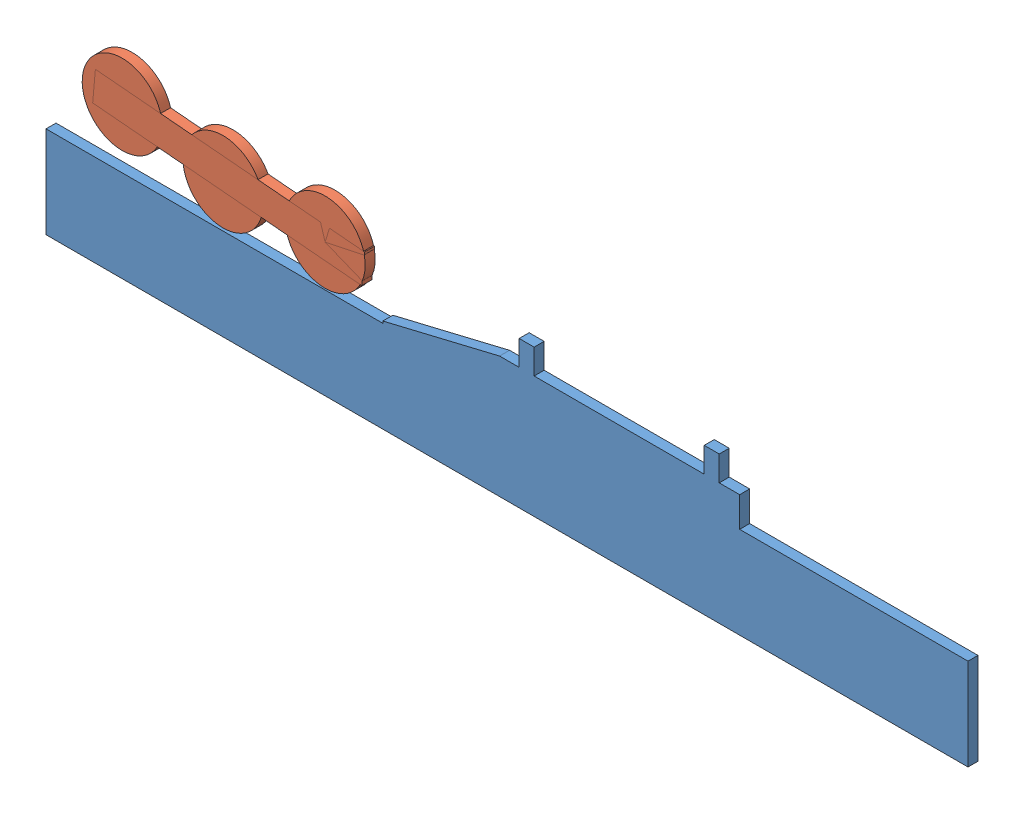
SolidWorks assembly Assem1, configuration Default. Lengths in mm.
Overall size (2340.68 493.45 25.4).
2 component instances, 2 part files, 1 mates.
Components (placement in the parent):
- Part1-2: Part1 [Default] at (-10.4189 -6.0319 9.5958) size (2340.68 372.5 25.4)
- SideViewFrame-1: SideViewFrame [Default] at (-657.1123 92.7426 9.5958) x (0.996152 -0.08764 0) z (0 0 1) size (720.34 222.76 25.4)
Mates (geometry in assembly coordinates):
- Coincident10: coincident: plane of Part1-2 through (-10.4189 -6.0319 34.9958) normal (0 0 1); plane of SideViewFrame-1 through (-1199.045 61.4729 34.9958) normal (0 0 1)
